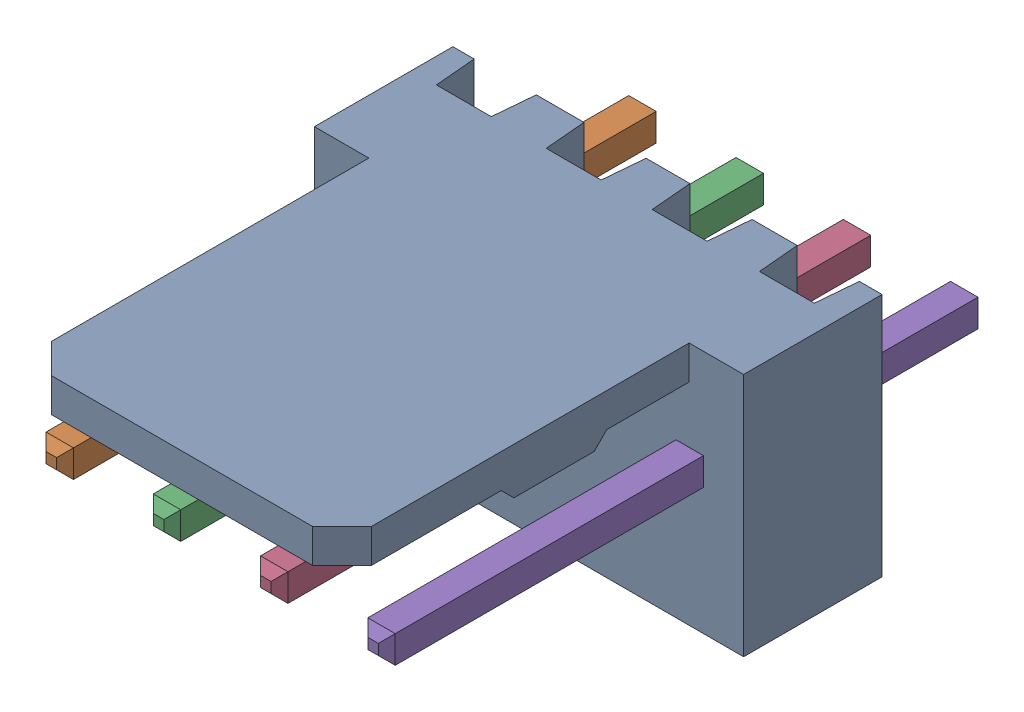
SolidWorks assembly Molex PCB 4 pin v3_3, configuration Default. Lengths in mm.
Overall size (10.16 5.79 14.92).
5 component instances, 2 part files, 0 mates.
Components (placement in the parent):
- BASE9710016 (2)-1: BASE9710016 (2) [Default] at (2.54 2.895 -8.22) size (10.16 5.79 11.5)
- PINO9710016 (2)-1: PINO9710016 (2) [Default] at (1.27 3.325 -0.72) size (0.65 0.65 14.2)
- PINO9710016 (2)-2: PINO9710016 (2) [Default] at (3.81 3.325 -0.72) size (0.65 0.65 14.2)
- PINO9710016 (2)-3: PINO9710016 (2) [Default] at (6.35 3.325 -0.72) size (0.65 0.65 14.2)
- PINO9710016 (2)-4: PINO9710016 (2) [Default] at (8.89 3.325 -0.72) size (0.65 0.65 14.2)
